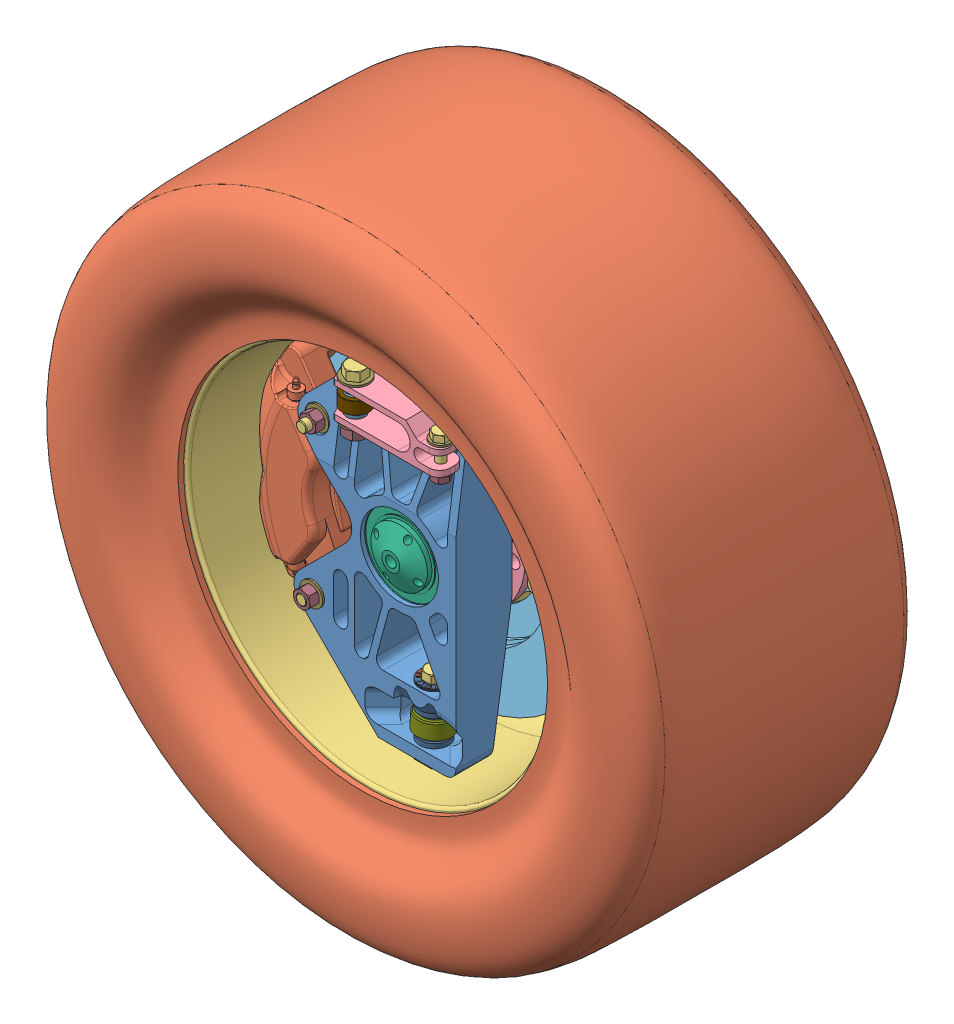
SolidWorks assembly CornerLF_Complete, configuration Default. Lengths in mm.
Overall size (777.29 777.29 255.79).
80 component instances, 30 part files, 180 mates.
Components (placement in the parent):
- UprighntLFLugBillet-4: UprighntLFLugBillet [Final Part] at origin size (558 599.44 88.5)
- TireFront-2: TireFront [Default] at (0 0 -3.67) x (-0.562655 -0.826691 0) z (0 0 1) size (559.46 559.46 255.79)
- WheelFront7J13-2: WheelFront7J13 [Default] at (0 0 -6.73) x (-0.953763 -0.30056 0) z (0 0 -1) size (363 363 191.1)
- SteeringArm-2: SteeringArm [Finished Part Left] at (-42.5 126.5 57.625) size (110 32.34 39)
- BrakeDiscWilwood160-3450-1: BrakeDiscWilwood160-3450 [Default] at (0 0 -3.38) x (-0.953763 -0.30056 0) z (0 0 1) size (266.7 266.7 20)
- BearingWheelCivicFront-1: BearingWheelCivicFront [Default] at (0 0 21.82) x (-0.973136 -0.230231 0) z (0 0 1) size (73.1 73.1 55.34)
- WheelNut-1: WheelNut [Default] at (-0.0272 -0.0421 -52.1943) x (0 0 -1) z (0.976774 0.21427 0) size (26.97 65 74.13)
- WheelDrivePin-1: WheelDrivePin [Default] at (45.3991 14.3067 -6.38) x (-0.73494 0.678133 0) z (0.678133 0.73494 0) size (19.05 44.86 17)
- WheelDrivePin-2: WheelDrivePin [Default] at (-45.3991 -14.3067 -6.38) x (0.925266 0.379318 0) z (0.379318 -0.925266 0) size (19.05 44.86 17)
- WheelDrivePin-3: WheelDrivePin [Default] at (-14.3067 45.3991 -6.38) x (0.256263 -0.966607 0) z (-0.966607 -0.256263 0) size (19.05 44.86 17)
- WheelDrivePin-4: WheelDrivePin [Default] at (14.3067 -45.3991 -6.38) x (0.572125 0.820166 0) z (0.820166 -0.572125 0) size (19.05 44.86 17)
- Pin625-1: Pin625 [Default] at (15.843 -96.8918 50.4139) size (25.4 58 20)
- Washer9x25x4-1: Washer9x25x4 [Default] at (15.843 -92.8918 50.4139) x (-0.99915 0 -0.041233) z (-0.041233 0 0.99915) size (25.4 4 25.4)
- Basic Internal Retaining Ring_am-1: Basic Internal Retaining Ring_am [B27.7M - 3BM1-72] at (0 0 21.667) x (0.998259 0.058987 0) z (0 0 1) size (76.5 74.92 2.4)
- Flat Washer Type A Narrow_AI-5: Flat Washer Type A Narrow_AI [Preferred Narrow FW 0.3125] at (-29.5 126.5 68.625) x (0 0 -1) z (-0.926229 0.376962 0) size (1.65 17.48 17.48)
- Flat Washer Type A Narrow_AI-6: Flat Washer Type A Narrow_AI [Preferred Narrow FW 0.3125] at (32.5 126.5 68.625) x (0 0 -1) z (-0.352455 -0.935829 0) size (1.65 17.48 17.48)
- Flat Washer Type A Narrow_AI-7: Flat Washer Type A Narrow_AI [Preferred Narrow FW 0.3125] at (32.5 126.5 40.625) x (0 0 1) z (1 0 0) size (1.65 17.48 17.48)
- Flat Washer Type A Narrow_AI-8: Flat Washer Type A Narrow_AI [Preferred Narrow FW 0.3125] at (-29.5 126.5 40.625) x (0 0 1) z (-1 -0.000001 0) size (1.65 17.48 17.48)
- Hex Nut_AI-7: Hex Nut_AI [HNUT 0.3125-24-D-N] at (32.5 126.5 32.0398) x (0.923728 0.383049 0) z (0 0 -1) size (12.7 14.66 6.93)
- Hex Nut_AI-8: Hex Nut_AI [HNUT 0.3125-24-D-N] at (-29.5 126.5 32.0398) x (0.923728 0.383049 0) z (0 0 -1) size (12.7 14.66 6.93)
- bush437x500x345-1: bush437x500x345 [Default] at (-16.1 133.7499 88.525) x (-0.828182 0 0.56046) z (-0.56046 0 -0.828182) size (16 8.75 16)
- bush437x500x345-2: bush437x500x345 [Default] at (-16.1 119.2501 88.525) x (0.498132 0 0.867101) z (0.867101 0 -0.498132) size (16 8.75 16)
- BearingSpherical625-1: BearingSpherical625 [Default] at (15.843 -125.485 50.4139) x (0.935451 0 -0.353457) z (0.353457 0 0.935451) size (34.77 22.58 34.87) (flexible)
  - SphericalBearingBall625-1: SphericalBearingBall625 [Default] x (1 0 0) z (0 -1 0) size (26.97 32.6 22.58)
  - SphericalBeaingRace625-1: SphericalBeaingRace625 [Default] x (0.988426 -0.029089 0.148889) z (-0.035405 -0.998574 0.039949) size (30.16 30.16 14.4)
- SpacerSteeringArm3mm-1: SpacerSteeringArm3mm [Default] at (-29.5 126.5 48.625) size (26 32 3)
- SpacerSteeringArm3mm-2: SpacerSteeringArm3mm [Default] at (-29.5 126.5 51.625) x (1 0 0) z (0 0 -1) size (26 32 3)
- SpacerSteeringArm3mm-3: SpacerSteeringArm3mm [Default] at (32.5 126.5 48.625) x (-1 0 0) z (0 0 1) size (26 32 3)
- SpacerSteeringArm3mm-4: SpacerSteeringArm3mm [Default] at (32.5 126.5 51.625) x (-1 0 0) z (0 0 1) size (26 32 3)
- SphericalBearing437in-1: SphericalBearing437in [Default] at (-16.1 126.5 88.525) x (0.999488 0 -0.032002) z (0 -1 0) size (23.81 23.81 14.27) (flexible)
  - SphericalBearing437Race-1: SphericalBearing437Race [Default] at origin size (23.81 23.81 11.23)
  - SphericalBearing437Ball-1: SphericalBearing437Ball [Default] at origin size (19.84 19.84 14.27)
- CaliperWilwood120-6816-1: CaliperWilwood120-6816 [Default] at (-77.1694 0 31.975) x (0 1 0) z (0 0 1) size (178.34 86.45 111.92)
- Flat Washer Type A Narrow_AI-1: Flat Washer Type A Narrow_AI [Preferred Narrow FW 0.375] at (-77.1694 66.7 27.025) x (0 0 1) z (-0.886278 -0.463153 0) size (1.65 20.62 20.62)
- Flat Washer Type A Narrow_AI-2: Flat Washer Type A Narrow_AI [Preferred Narrow FW 0.375] at (-77.1694 -66.7 27.025) x (0 0 1) z (-0.723569 -0.690252 0) size (1.65 20.62 20.62)
- Flat Washer Type A Narrow_AI-3: Flat Washer Type A Narrow_AI [Preferred Narrow FW 0.375] at (-77.1694 -66.7 65.625) x (0 0 -1) z (1 0 0) size (1.65 20.62 20.62)
- Flat Washer Type A Narrow_AI-4: Flat Washer Type A Narrow_AI [Preferred Narrow FW 0.375] at (-77.1694 66.7 60.225) x (0 0 -1) z (1 0 0) size (1.65 20.62 20.62)
- Hex Bolt_AI-1: Hex Bolt_AI [HBOLT 0.3750-24x2x1-N] at (-77.1694 66.7 18.5668) x (0 0 1) z (-1 0 0) size (57.61 16.48 14.27)
- Hex Bolt_AI-2: Hex Bolt_AI [HBOLT 0.3750-24x2x1-N] at (-77.1694 -66.7 18.5668) x (0 0 1) z (-1 0 0) size (57.61 16.48 14.27)
- Hex Nut_AI-1: Hex Nut_AI [HNUT 0.3750-24-D-N] at (-77.1694 66.7 70.4358) size (14.27 16.48 8.56)
- Hex Nut_AI-2: Hex Nut_AI [HNUT 0.3750-24-D-N] at (-77.1694 -66.7 75.8358) x (-0.310782 -0.950481 0) z (0 0 1) size (14.27 16.48 8.56)
- WheelHubHondaCivic-1: WheelHubHondaCivic [Default] at (0 0 21.82) x (-0.996181 0.087308 0) z (0 0 -1) size (120.8 125.54 59.3)
- AdapterWheelHubToDisc-1: AdapterWheelHubToDisc [Finished Part] at (0 0 5.62) x (-0.953763 -0.30056 0) z (0 0 1) size (138.98 157.7 6)
- CVjointCivicOuterMod-1: CVjointCivicOuterMod [Default] at (0 0 116.42) x (0 0 -1) z (0.454803 0.890592 0) size (91.51 50.5 50.5)
- NutHondaCivWhlBrngRet-1: NutHondaCivWhlBrngRet [Default] at (0 0 -2.08) x (-0.872533 0.488555 0) z (0 0 -1) size (36.6 36.6 19.8)
- AxleStub-1: AxleStub [Default] at (0 0 3.92) x (0.99636 -0.085241 0) z (0 0 1) size (56.9 57.5 80.26)
- Flat Washer Type A Narrow_AI-23: Flat Washer Type A Narrow_AI [Preferred Narrow FW 0.3125] at (20.9941 -66.6203 5.62) x (0 0 -1) z (1 0 0) size (1.65 17.48 17.48)
- Flat Washer Type A Narrow_AI-24: Flat Washer Type A Narrow_AI [Preferred Narrow FW 0.3125] at (-47.1978 -51.4916 5.62) x (0 0 -1) z (1 0 0) size (1.65 17.48 17.48)
- Flat Washer Type A Narrow_AI-25: Flat Washer Type A Narrow_AI [Preferred Narrow FW 0.3125] at (-68.192 15.1287 5.62) x (0 0 -1) z (1 0 0) size (1.65 17.48 17.48)
- Flat Washer Type A Narrow_AI-26: Flat Washer Type A Narrow_AI [Preferred Narrow FW 0.3125] at (-20.9941 66.6203 5.62) x (0 0 -1) z (1 0 0) size (1.65 17.48 17.48)
- Flat Washer Type A Narrow_AI-27: Flat Washer Type A Narrow_AI [Preferred Narrow FW 0.3125] at (47.1978 51.4916 5.62) x (0 0 -1) z (1 0 0) size (1.65 17.48 17.48)
- Flat Washer Type A Narrow_AI-28: Flat Washer Type A Narrow_AI [Preferred Narrow FW 0.3125] at (68.192 -15.1287 5.62) x (0 0 -1) z (1 0 0) size (1.65 17.48 17.48)
- Hex Bolt_AI-3: Hex Bolt_AI [HBOLT 0.3125-24x0.75x0.75-N] at (20.9941 -66.6203 13.24) x (0 0 -1) z (1 0 0) size (25.02 14.66 12.7)
- Hex Bolt_AI-4: Hex Bolt_AI [HBOLT 0.3125-24x0.75x0.75-N] at (-47.1978 -51.4916 13.24) x (0 0 -1) z (1 0 0) size (25.02 14.66 12.7)
- Hex Bolt_AI-5: Hex Bolt_AI [HBOLT 0.3125-24x0.75x0.75-N] at (-68.192 15.1287 13.24) x (0 0 -1) z (1 0 0) size (25.02 14.66 12.7)
- Hex Bolt_AI-6: Hex Bolt_AI [HBOLT 0.3125-24x0.75x0.75-N] at (-20.9941 66.6203 13.24) x (0 0 -1) z (1 0 0) size (25.02 14.66 12.7)
- Hex Bolt_AI-7: Hex Bolt_AI [HBOLT 0.3125-24x0.75x0.75-N] at (47.1978 51.4916 13.24) x (0 0 -1) z (1 0 0) size (25.02 14.66 12.7)
- Hex Bolt_AI-8: Hex Bolt_AI [HBOLT 0.3125-24x0.75x0.75-N] at (68.192 -15.1287 13.24) x (0 0 -1) z (1 0 0) size (25.02 14.66 12.7)
- Hex Nut_AI-16: Hex Nut_AI [HNUT 0.3125-24-D-N] at (20.9941 -66.6203 -10.3142) x (0.923728 0.383049 0) z (0 0 -1) size (12.7 14.66 6.93)
- Hex Nut_AI-17: Hex Nut_AI [HNUT 0.3125-24-D-N] at (68.192 -15.1287 -3.38) x (0.080122 0.996785 0) z (0 0 1) size (12.7 14.66 6.93)
- Hex Nut_AI-18: Hex Nut_AI [HNUT 0.3125-24-D-N] at (47.1978 51.4916 -10.3142) x (0.923728 0.383049 0) z (0 0 -1) size (12.7 14.66 6.93)
- Hex Nut_AI-19: Hex Nut_AI [HNUT 0.3125-24-D-N] at (-20.9941 66.6203 -10.3142) x (0.923728 0.383049 0) z (0 0 -1) size (12.7 14.66 6.93)
- Hex Nut_AI-20: Hex Nut_AI [HNUT 0.3125-24-D-N] at (-68.192 15.1287 -10.3142) x (0.923728 0.383049 0) z (0 0 -1) size (12.7 14.66 6.93)
- Hex Nut_AI-21: Hex Nut_AI [HNUT 0.3125-24-D-N] at (-47.1978 -51.4916 -10.3142) x (0.923728 0.383049 0) z (0 0 -1) size (12.7 14.66 6.93)
- SpacerWheelHubToWheel-1: SpacerWheelHubToWheel [Default] at (0 0 -6.73) x (-0.953763 -0.30056 0) z (0 0 1) size (117.5 117.5 6.35)
- Bush16x19x4-1: Bush16x19x4 [Lower Bushing] at (15.843 -139.2 50.4139) x (-0.837169 0 -0.546944) z (0.546944 0 -0.837169) size (25.4 13.9 25.4)
- Bush16x19x4-2: Bush16x19x4 [Upper Bushing] at (15.843 -111.86 50.4139) x (0.401704 0 0.915769) z (0.915769 0 -0.401704) size (25.4 20.96 25.4)
- Flat Washer Type A Narrow_AI-29: Flat Washer Type A Narrow_AI [Preferred Narrow FW 0.4375] at (-16.1 142.5 88.525) x (0 -1 0) z (-0.546944 0 -0.837169) size (1.65 23.42 23.42)
- Flat Washer Type A Narrow_AI-30: Flat Washer Type A Narrow_AI [Preferred Narrow FW 0.4375] at (-16.1 110.5 88.525) x (0 1 0) z (0.546944 0 0.837169) size (1.65 23.42 23.42)
- Hex Nut_AI-22: Hex Nut_AI [HNUT 0.4375-20-D-N] at (-16.1 99.07 88.525) x (-0.837169 0 0.546944) z (0 -1 0) size (17.48 20.18 9.78)
- Flat Washer Type A Narrow_AI-31: Flat Washer Type A Narrow_AI [Preferred Narrow FW 0.3125] at (59.9 110.5 88.525) x (0 1 0) z (0.546944 0 0.837169) size (1.65 17.48 17.48)
- Flat Washer Type A Narrow_AI-32: Flat Washer Type A Narrow_AI [Preferred Narrow FW 0.3125] at (59.9 132.0562 88.525) x (0 -1 0) z (-0.546944 0 -0.837169) size (1.65 17.48 17.48)
- Hex Nut_AI-23: Hex Nut_AI [HNUT 0.3125-24-D-N] at (59.9 101.9148 88.525) x (-0.837169 0 0.546944) z (0 -1 0) size (12.7 14.66 6.93)
- Hex Bolt_AI-9: Hex Bolt_AI [HBOLT 0.4375-20x1.75x1.75-N] at (-16.1 152.1774 88.525) x (0 -1 0) z (-0.546944 0 -0.837169) size (52.48 18.33 15.88)
- Hex Bolt_AI-10: Hex Bolt_AI [HBOLT 0.3125-24x1.25x1.25-N] at (59.9 139.6763 88.525) x (0 -1 0) z (-0.546944 0 -0.837169) size (37.72 14.66 12.7)
- Hex Bolt_AI-11: Hex Bolt_AI [HBOLT 0.375-24x1x1-N] at (15.843 -86.0846 50.4139) x (0 -1 0) z (0 0 1) size (32.21 16.48 14.27)
- Hex Bolt_AI-12: Hex Bolt_AI [HBOLT 0.3125-24x1.375x0.875-N] at (-29.5 126.5 76.245) x (0 0 -1) z (1 0 0) size (40.89 14.66 12.7)
- Hex Bolt_AI-13: Hex Bolt_AI [HBOLT 0.3125-24x1.375x0.875-N] at (32.5 126.5 76.245) x (0 0 -1) z (1 0 0) size (40.89 14.66 12.7)
- Flat Washer Type A Wide_AI-1: Flat Washer Type A Wide_AI [Preferred Wide FW 0.375] at (15.843 -92.8918 50.4139) x (0 1 0) z (1 0 0) size (2.11 25.4 25.4)
- AxleStubPin-1: AxleStubPin [Default] at (1.3162 15.0174 3.17) size (6.35 6.35 9.5)
Mates (geometry in assembly coordinates):
- Concentric1: concentric: cylinder of assembly; cone of assembly; cylinder of TireFront-2 through (0 0 142.5814) axis (0 0 1) radius 165; cone of WheelFront7J13-2 through (0 0 83.0288) axis (0 0 -1)
- Concentric241: concentric: cylinder of assembly; cylinder of assembly; cylinder of Pin625-1 through (15.843 -150.8918 50.4139) axis (0 1 0) radius 7.9375; cylinder of UprighntLFLugBillet-4 through (15.843 -149 50.4139) axis (0 1 0) radius 9.525
- Concentric251: concentric: cylinder of assembly; cylinder of assembly; cylinder of Washer9x25x4-1 through (15.843 -96.8918 50.4139) axis (0 1 0) radius 4.7625; cylinder of Pin625-1 through (15.843 -150.8918 50.4139) axis (0 1 0) radius 7.9375
- Coincident221: coincident: plane of assembly; plane of assembly; plane of Pin625-1 through (15.843 -96.8918 50.4139) normal (0 1 0); plane of Washer9x25x4-1 through (15.843 -96.8918 50.4139) normal (0 -1 0)
- Concentric2621: concentric: cylinder of assembly; cylinder of assembly; cylinder of Basic Internal Retaining Ring_am-1 through (0 0 19.267) axis (0 0 1) radius 38.25; cylinder of UprighntLFLugBillet-4 through (0 0 61.82) axis (0 0 -1) radius 36.5
- Concentric26221: concentric: cylinder of assembly; cylinder of assembly; cylinder of SteeringArm-2 through (-29.5 126.5 99.625) axis (0 0 -1) radius 4.1021; cylinder of Flat Washer Type A Narrow_AI-5 through (-29.5 126.5 103.55) axis (0 0 1) radius 4.3688
- Coincident2321: coincident: plane of assembly; plane of SteeringArm-2 through (12.8365 126.7309 68.625) normal (0 0 1); plane of Flat Washer Type A Narrow_AI-5 through (-31.1469 122.4535 68.625) normal (0 0 -1)
- Concentric26231: concentric: cylinder of assembly; cylinder of assembly; cylinder of SteeringArm-2 through (32.5 126.5 99.625) axis (0 0 -1) radius 4.1021; cylinder of Flat Washer Type A Narrow_AI-6 through (32.5 126.5 103.55) axis (0 0 1) radius 4.3688
- Coincident2331: coincident: plane of assembly; plane of assembly; plane of SteeringArm-2 through (12.8365 126.7309 68.625) normal (0 0 1); plane of Flat Washer Type A Narrow_AI-6 through (36.5884 124.9602 68.625) normal (0 0 -1)
- Coincident2341: coincident: plane of assembly; plane of assembly; plane of UprighntLFLugBillet-4 through (38.5625 118.4375 40.625) normal (0 0 -1); plane of Flat Washer Type A Narrow_AI-7 through (32.5 122.1312 40.625) normal (0 0 1)
- Coincident2351: coincident: plane of assembly; plane of assembly; plane of UprighntLFLugBillet-4 through (38.5625 118.4375 40.625) normal (0 0 -1); plane of Flat Washer Type A Narrow_AI-8 through (-29.5 130.8688 40.625) normal (0 0 1)
- Concentric26291: concentric: cylinder of assembly; cylinder of assembly; cylinder of Flat Washer Type A Narrow_AI-7 through (32.5 126.5 5.7) axis (0 0 -1) radius 4.3688; cylinder of Hex Nut_AI-7 through (32.5 126.5 57.0773) axis (0 0 -1) radius 3.9688
- Coincident2391: coincident: plane of assembly; plane of assembly; plane of Flat Washer Type A Narrow_AI-7 through (32.5 117.7624 38.974) normal (0 0 -1); plane of Hex Nut_AI-7 through (35.3086 119.7269 38.974) normal (0 0 1)
- Concentric26301: concentric: cylinder of assembly; cylinder of assembly; cylinder of Flat Washer Type A Narrow_AI-8 through (-29.5 126.5 5.7) axis (0 0 -1) radius 4.3688; cylinder of Hex Nut_AI-8 through (-29.5 126.5 57.0773) axis (0 0 -1) radius 3.9688
- Coincident2401: coincident: plane of assembly; plane of assembly; plane of Flat Washer Type A Narrow_AI-8 through (-29.5 135.2376 38.974) normal (0 0 -1); plane of Hex Nut_AI-8 through (-26.6914 119.7269 38.974) normal (0 0 1)
- Concentric2636: concentric: cylinder of assembly; cylinder of assembly; cylinder of SteeringArm-2 through (-16.1 110.5 88.525) axis (0 1 0) radius 6.35; cylinder of bush437x500x345-1 through (-16.1 137.6125 88.525) axis (0 -1 0) radius 5.5563
- Concentric2637: concentric: cylinder of assembly; cylinder of assembly; cylinder of SteeringArm-2 through (-16.1 110.5 88.525) axis (0 1 0) radius 6.35; cylinder of bush437x500x345-2 through (-16.1 115.3875 88.525) axis (0 1 0) radius 5.5563
- Coincident245: coincident: plane of assembly; plane of assembly; plane of SteeringArm-2 through (-42.5 137.6125 135.625) normal (0 -1 0); plane of bush437x500x345-1 through (-16.1 137.6125 88.525) normal (0 1 0)
- Coincident246: coincident: plane of assembly; plane of assembly; plane of SteeringArm-2 through (-42.5 115.3875 135.625) normal (0 1 0); plane of bush437x500x345-2 through (-16.1 115.3875 88.525) normal (0 -1 0)
- Distance1: distance = 12 mm: plane of assembly; plane of assembly; plane of UprighntLFLugBillet-4 through (38.5625 118.4375 48.625) normal (0 0 1); plane of SteeringArm-2 through (-42.5 142.5 60.625) normal (0 0 -1)
- Concentric26303: concentric: cylinder of assembly; cylinder of assembly; cylinder of Pin625-1 through (15.843 -150.8918 50.4139) axis (0 1 0) radius 7.9375; cylinder of BearingSpherical625-1/SphericalBearingBall625-1 through (15.843 -115.5936 50.4139) axis (0 1 0) radius 7.94
- Coincident2402: coincident: point of UprighntLFLugBillet-4; point of BearingSpherical625-1/SphericalBearingBall625-1
- Coincident2406: coincident: plane of assembly; plane of assembly; plane of SpacerSteeringArm3mm-1 through (-14.5 110.5 48.625) normal (0 0 -1); plane of UprighntLFLugBillet-4 through (38.5625 118.4375 48.625) normal (0 0 1)
- Concentric26308: concentric: cylinder of assembly; cylinder of assembly; cylinder of SpacerSteeringArm3mm-3 through (32.5 126.5 51.625) axis (0 0 -1) radius 4.1021; cylinder of SpacerSteeringArm3mm-4 through (32.5 126.5 54.625) axis (0 0 -1) radius 4.1021
- Coincident2407: coincident: plane of assembly; plane of assembly; plane of SpacerSteeringArm3mm-3 through (17.5 142.5 51.625) normal (0 0 1); plane of SpacerSteeringArm3mm-4 through (17.5 142.5 51.625) normal (0 0 -1)
- Coincident2408: coincident: plane of assembly; plane of assembly; plane of SpacerSteeringArm3mm-1 through (-14.5 110.5 51.625) normal (0 0 1); plane of SpacerSteeringArm3mm-2 through (-14.5 142.5 51.625) normal (0 0 1)
- Coincident2409: coincident: plane of assembly; plane of assembly; plane of SpacerSteeringArm3mm-3 through (17.5 142.5 48.625) normal (0 0 -1); plane of UprighntLFLugBillet-4 through (38.5625 118.4375 48.625) normal (0 0 1)
- Concentric26310: concentric: cylinder of SteeringArm-2 through (-16.1 110.5 88.525) axis (0 1 0) radius 6.35; cylinder of ? through (-16.1 132.1134 88.525) axis (0 -1 0) radius 11.9062
- Concentric26311: concentric: sphere of SteeringArm-2; unknown of ?
- Distance4: distance = 102 mm: line of CaliperWilwood120-6816-1 through (-77.1694 66.7 31.975) axis (0 0 1); line of BearingWheelCivicFront-1 through (0 0 13.2488) axis (0 0 1)
- Distance5: distance = 102 mm: line of CaliperWilwood120-6816-1 through (-77.1694 -66.7 49.225) axis (0 0 -1); line of BearingWheelCivicFront-1 through (0 0 13.2488) axis (0 0 1)
- Parallel1: parallel: plane of assembly through (0 0 0) normal (0 0 1); plane of CaliperWilwood120-6816-1 through (-77.1694 0 31.975) normal (0 0 1); plane of assembly
- Distance6: distance = 10.287 mm: plane of assembly; plane of assembly; plane of BrakeDiscWilwood160-3450-1 through (0 0 -3.38) normal (0 0 1); plane of CaliperWilwood120-6816-1 through (-77.1694 0 7.075) normal (0 0 1)
- Parallel2: parallel: plane of assembly through (0 0 0) normal (1 0 0); plane of CaliperWilwood120-6816-1 through (-77.1694 0 31.975) normal (-1 0 0); plane of assembly
- Concentric263402: concentric: cylinder of Flat Washer Type A Narrow_AI-1 through (-77.1694 66.7 -7.9) axis (0 0 -1) radius 5.1562; cylinder of Hex Bolt_AI-1 through (-77.1694 66.7 18.5668) axis (0 0 -1) radius 4.7625
- Coincident24383: coincident: plane of UprighntLFLugBillet-4 through (-77.191 66.675 27.025) normal (0 0 -1); plane of Flat Washer Type A Narrow_AI-1 through (-79.5575 71.2698 27.025) normal (0 0 1)
- Concentric263403: concentric: cylinder of Flat Washer Type A Narrow_AI-2 through (-77.1694 -66.7 -7.9) axis (0 0 -1) radius 5.1562; cylinder of Hex Bolt_AI-2 through (-77.1694 -66.7 18.5668) axis (0 0 -1) radius 4.7625
- Coincident24384: coincident: plane of UprighntLFLugBillet-4 through (-77.191 -66.675 27.025) normal (0 0 -1); plane of Flat Washer Type A Narrow_AI-2 through (-80.7284 -62.9691 27.025) normal (0 0 1)
- Coincident24385: coincident: plane of UprighntLFLugBillet-4 through (0 0 65.625) normal (0 0 1); plane of Flat Washer Type A Narrow_AI-3 through (-77.1694 -61.5438 65.625) normal (0 0 -1)
- Concentric263405: concentric: cylinder of Flat Washer Type A Narrow_AI-4 through (-77.1694 66.7 95.15) axis (0 0 1) radius 5.1562; cylinder of Hex Bolt_AI-1 through (-77.1694 66.7 18.5668) axis (0 0 -1) radius 4.7625
- Coincident24386: coincident: plane of UprighntLFLugBillet-4 through (-77.191 66.675 60.225) normal (0 0 1); plane of Flat Washer Type A Narrow_AI-4 through (-77.1694 71.8562 60.225) normal (0 0 -1)
- Coincident24387: coincident: plane of Flat Washer Type A Narrow_AI-1 through (-81.9456 75.8397 25.374) normal (0 0 -1); plane of Hex Bolt_AI-1 through (-77.1694 74.9416 25.374) normal (0 0 1)
- Coincident24388: coincident: plane of Flat Washer Type A Narrow_AI-2 through (-84.2875 -59.2383 25.374) normal (0 0 -1); plane of Hex Bolt_AI-2 through (-77.1694 -58.4584 25.374) normal (0 0 1)
- Concentric263408: concentric: cylinder of Hex Bolt_AI-1 through (-77.1694 66.7 18.5668) axis (0 0 -1) radius 4.7625; cylinder of Hex Nut_AI-1 through (-77.1694 66.7 45.3983) axis (0 0 1) radius 4.7625
- Coincident24389: coincident: plane of Flat Washer Type A Narrow_AI-4 through (-77.1694 77.0124 61.876) normal (0 0 1); plane of Hex Nut_AI-1 through (-91.4442 66.7 61.876) normal (0 0 -1)
- Concentric263409: concentric: cylinder of Hex Bolt_AI-2 through (-77.1694 -66.7 18.5668) axis (0 0 -1) radius 4.7625; cylinder of Hex Nut_AI-2 through (-77.1694 -66.7 50.7983) axis (0 0 1) radius 4.7625
- Coincident24390: coincident: plane of Flat Washer Type A Narrow_AI-3 through (-77.1694 -56.3876 67.276) normal (0 0 1); plane of Hex Nut_AI-2 through (-72.733 -53.1321 67.276) normal (0 0 -1)
- Coincident24406: coincident: plane of UprighntLFLugBillet-4 through (38.5 -147.031 -21.5) normal (0 -1 0); plane of ? through (15.843 -149 50.4139) normal (0 1 0)
- Concentric263421: concentric: cylinder of ? through (15.843 -109.031 -50.4139) axis (0 1 0) radius 3.4544; cylinder of ? through (15.843 -95 50.4139) axis (0 1 0) radius 4.7625
- Coincident24407: coincident: plane of ? through (15.843 -95 50.4139) normal (0 1 0); plane of ? through (20.6055 -99.031 -50.4139) normal (0 -1 0)
- Concentric263423: concentric: cylinder of assembly; cylinder of assembly; cylinder of SteeringArm-2 through (-29.5 126.5 99.625) axis (0 0 1) radius 4.1021; cylinder of Flat Washer Type A Narrow_AI-5 through (-29.5 126.5 103.55) axis (0 0 1) radius 4.3688
- Coincident24409: coincident: plane of ? through (12.8365 126.7309 -60.2175) normal (0 0 -1); plane of Flat Washer Type A Narrow_AI-5 through (-31.1469 122.4535 68.625) normal (0 0 -1)
- Concentric263424: concentric: cylinder of assembly; cylinder of assembly; cylinder of SteeringArm-2 through (32.5 126.5 99.625) axis (0 0 -1) radius 4.1021; cylinder of Flat Washer Type A Narrow_AI-6 through (32.5 126.5 103.55) axis (0 0 1) radius 4.3688
- Coincident24410: coincident: plane of ? through (12.8365 126.7309 -60.2175) normal (0 0 -1); plane of Flat Washer Type A Narrow_AI-6 through (36.5884 124.9602 68.625) normal (0 0 -1)
- Concentric263425: concentric: cylinder of assembly; cylinder of UprighntLFLugBillet-4 through (29.5 126.5 -40.2175) axis (0 0 -1) radius 3.9688; cylinder of Flat Washer Type A Narrow_AI-7 through (32.5 126.5 5.7) axis (0 0 -1) radius 4.3688
- Coincident24411: coincident: plane of assembly; plane of assembly; plane of UprighntLFLugBillet-4 through (38.5625 118.4375 48.625) normal (0 0 1); plane of Flat Washer Type A Narrow_AI-7 through (32.5 122.1312 40.625) normal (0 0 1)
- Coincident24415: coincident: plane of assembly; plane of assembly; plane of Flat Washer Type A Narrow_AI-7 through (32.5 117.7624 38.974) normal (0 0 -1); plane of Hex Nut_AI-7 through (35.3086 119.7269 32.0398) normal (0 0 -1)
- Coincident24417: coincident: plane of assembly; plane of assembly; plane of UprighntLFLugBillet-4 through (34.0068 0 19.267) normal (0 0 1); plane of Basic Internal Retaining Ring_am-1 through (0 0 19.267) normal (0 0 -1)
- Concentric263429: concentric: cylinder of assembly; cylinder of UprighntLFLugBillet-4 through (-29.5 126.5 -40.2175) axis (0 0 -1) radius 3.9688; cylinder of SteeringArm-2 through (-29.5 126.5 99.625) axis (0 0 1) radius 4.1021
- Concentric263430: concentric: cylinder of assembly; cylinder of UprighntLFLugBillet-4 through (29.5 126.5 -40.2175) axis (0 0 -1) radius 3.9688; cylinder of SteeringArm-2 through (32.5 126.5 99.625) axis (0 0 -1) radius 4.1021
- Concentric263431: concentric: cylinder of assembly; cylinder of assembly; cylinder of SteeringArm-2 through (-16.1 110.5 88.525) axis (0 1 0) radius 6.35; cylinder of bush437x500x345-1 through (-16.1 137.6125 88.525) axis (0 -1 0) radius 5.5563
- Concentric263432: concentric: cylinder of assembly; cylinder of assembly; cylinder of SteeringArm-2 through (-16.1 110.5 88.525) axis (0 1 0) radius 6.35; cylinder of bush437x500x345-2 through (-16.1 115.3875 88.525) axis (0 1 0) radius 5.5563
- Coincident24418: coincident: plane of assembly; plane of assembly; plane of SteeringArm-2 through (-42.5 137.6125 135.625) normal (0 -1 0); plane of bush437x500x345-1 through (-16.1 137.6125 88.525) normal (0 1 0)
- Coincident24419: coincident: plane of ? through (-42.5 115.5 -129.2175) normal (0 1 0); plane of bush437x500x345-2 through (-16.1 119.2501 88.525) normal (0 1 0)
- Distance7: distance = 6 mm: plane of assembly; plane of UprighntLFLugBillet-4; plane of SteeringArm-2 through (-42.5 142.5 60.625) normal (0 0 -1)
- Coincident24421: coincident: plane of assembly; plane of UprighntLFLugBillet-4; plane of SpacerSteeringArm3mm-1 through (-14.5 110.5 48.625) normal (0 0 -1)
- Concentric263438: concentric: cylinder of assembly; cylinder of assembly; cylinder of SpacerSteeringArm3mm-3 through (32.5 126.5 51.625) axis (0 0 1) radius 4.1021; cylinder of SpacerSteeringArm3mm-4 through (32.5 126.5 54.625) axis (0 0 1) radius 4.1021
- Coincident24422: coincident: plane of assembly; plane of assembly; plane of SpacerSteeringArm3mm-3 through (17.5 142.5 51.625) normal (0 0 1); plane of SpacerSteeringArm3mm-4 through (17.5 142.5 51.625) normal (0 0 -1)
- Coincident24423: coincident: plane of assembly; plane of assembly; plane of SpacerSteeringArm3mm-1 through (-14.5 110.5 51.625) normal (0 0 1); plane of SpacerSteeringArm3mm-2 through (-14.5 142.5 51.625) normal (0 0 1)
- Coincident24424: coincident: plane of assembly; plane of UprighntLFLugBillet-4; plane of SpacerSteeringArm3mm-3 through (17.5 142.5 48.625) normal (0 0 -1)
- Concentric263470: concentric: cylinder of assembly; cylinder of assembly; cylinder of BearingWheelCivicFront-1 through (0 0 61.82) axis (0 0 -1) radius 19; cylinder of WheelHubHondaCivic-1 through (0 0 21.82) axis (0 0 1) radius 19
- Concentric263471: concentric: cylinder of assembly; cylinder of assembly; cylinder of UprighntLFLugBillet-4 through (0 0 61.82) axis (0 0 -1) radius 36.5; cylinder of BearingWheelCivicFront-1 through (0 0 61.82) axis (0 0 -1) radius 36.55
- Coincident24471: coincident: plane of assembly; plane of assembly; plane of UprighntLFLugBillet-4 through (0 0 61.82) normal (0 0 -1); plane of BearingWheelCivicFront-1 through (0 0 61.82) normal (0 0 1)
- Coincident24472: coincident: plane of assembly; plane of assembly; plane of UprighntLFLugBillet-4 through (-94.191 13.875 49.225) normal (0 0 -1); plane of CaliperWilwood120-6816-1 through (-77.1694 -66.7 49.225) normal (0 0 1)
- Coincident24473: coincident: plane of assembly; plane of assembly; plane of BearingWheelCivicFront-1 through (0 0 21.82) normal (0 0 -1); plane of WheelHubHondaCivic-1 through (1.7025 19.4255 21.82) normal (0 0 1)
- Coincident24474: coincident: plane of assembly; plane of assembly; plane of WheelHubHondaCivic-1 through (5.2734 60.1694 5.62) normal (0 0 -1); plane of AdapterWheelHubToDisc-1 through (9.137 -28.9944 5.62) normal (0 0 1)
- Concentric263474: concentric: cylinder of assembly; cylinder of assembly; cylinder of WheelHubHondaCivic-1 through (0 0 21.82) axis (0 0 1) radius 14.1; cylinder of CVjointCivicOuterMod-1 through (0 0 276.1473) axis (0 0 1) radius 13.5
- Coincident24476: coincident: plane of assembly; plane of assembly; plane of BearingWheelCivicFront-1 through (0 0 61.82) normal (0 0 1); plane of CVjointCivicOuterMod-1 through (-12.023 6.1398 61.82) normal (0 0 -1)
- Concentric263475: concentric: cylinder of assembly; cylinder of assembly; cylinder of SpacerWheelHubToWheel-1 through (0 0 -0.38) axis (0 0 -1) radius 58.75; cylinder of WheelHubHondaCivic-1 through (0 0 21.82) axis (0 0 1) radius 60.4
- Concentric263480: concentric: cylinder of assembly; cylinder of assembly; cylinder of CVjointCivicOuterMod-1 through (0 0 276.1473) axis (0 0 1) radius 10.9; cylinder of NutHondaCivWhlBrngRet-1 through (0 0 -29.8385) axis (0 0 -1) radius 10.2
- Concentric263481: concentric: cylinder of assembly; cylinder of assembly; cylinder of CVjointCivicOuterMod-1 through (0 0 276.1473) axis (0 0 1) radius 10.9; cylinder of AxleStub-1 through (0 0 50.1767) axis (0 0 1) radius 10.9
- Coincident24479: coincident: plane of assembly; plane of assembly; plane of NutHondaCivWhlBrngRet-1 through (4.9833 8.8998 -2.08) normal (0 0 1); plane of AxleStub-1 through (1.4619 17.0876 -2.08) normal (0 0 -1)
- Coincident24480: coincident: plane of assembly; plane of assembly; plane of WheelHubHondaCivic-1 through (1.2223 13.9465 3.92) normal (0 0 -1); plane of AxleStub-1 through (1.6452 19.2298 3.92) normal (0 0 1)
- Coincident24481: coincident: plane of assembly; plane of assembly; plane of WheelDrivePin-3 through (-16.7476 54.606 -0.38) normal (0 0 1); plane of AdapterWheelHubToDisc-1 through (17.6579 -56.0336 -0.38) normal (0 0 -1)
- Concentric263483: concentric: cylinder of assembly; cylinder of WheelDrivePin-3 through (-14.3067 45.3991 65.6665) axis (0 0 1) radius 9.525; cylinder of AdapterWheelHubToDisc-1 through (-14.3067 45.3991 -0.38) axis (0 0 1) radius 6.5481
- Concentric263484: concentric: cylinder of assembly; cylinder of assembly; cylinder of WheelDrivePin-2 through (-45.3991 -14.3067 65.6665) axis (0 0 1) radius 6.35; cylinder of WheelHubHondaCivic-1 through (-45.3991 -14.3067 5.62) axis (0 0 -1) radius 5.7544
- Coincident24482: coincident: plane of assembly; plane of assembly; plane of WheelDrivePin-2 through (-54.2123 -17.9197 -0.38) normal (0 0 1); plane of AdapterWheelHubToDisc-1 through (17.6579 -56.0336 -0.38) normal (0 0 -1)
- Concentric263486: concentric: cylinder of assembly; cylinder of assembly; cylinder of WheelDrivePin-4 through (14.3067 -45.3991 65.6665) axis (0 0 1) radius 6.35; cylinder of WheelHubHondaCivic-1 through (14.3067 -45.3991 5.62) axis (0 0 -1) radius 5.7544
- Coincident24483: coincident: plane of assembly; plane of assembly; plane of WheelDrivePin-4 through (8.8572 -53.2112 -0.38) normal (0 0 1); plane of AdapterWheelHubToDisc-1 through (17.6579 -56.0336 -0.38) normal (0 0 -1)
- Coincident24484: coincident: plane of assembly; plane of assembly; plane of WheelDrivePin-1 through (52.3994 7.8475 -0.38) normal (0 0 1); plane of AdapterWheelHubToDisc-1 through (17.6579 -56.0336 -0.38) normal (0 0 -1)
- Concentric263488: concentric: cylinder of assembly; cylinder of assembly; cylinder of BrakeDiscWilwood160-3450-1 through (0 0 -0.38) axis (0 0 -1) radius 62.75; cylinder of SpacerWheelHubToWheel-1 through (0 0 -0.38) axis (0 0 -1) radius 58.75
- Concentric263490: concentric: cylinder of assembly; cylinder of assembly; cylinder of AdapterWheelHubToDisc-1 through (20.9941 -66.6203 -0.38) axis (0 0 1) radius 4.1021; cylinder of Flat Washer Type A Narrow_AI-23 through (20.9941 -66.6203 40.545) axis (0 0 1) radius 4.3688
- Coincident24486: coincident: plane of assembly; plane of assembly; plane of AdapterWheelHubToDisc-1 through (9.137 -28.9944 5.62) normal (0 0 1); plane of Flat Washer Type A Narrow_AI-23 through (20.9941 -62.2515 5.62) normal (0 0 -1)
- Concentric263491: concentric: cylinder of assembly; cylinder of assembly; cylinder of AdapterWheelHubToDisc-1 through (-47.1978 -51.4916 -0.38) axis (0 0 1) radius 4.1021; cylinder of Flat Washer Type A Narrow_AI-24 through (-47.1978 -51.4916 40.545) axis (0 0 1) radius 4.3688
- Coincident24487: coincident: plane of assembly; plane of assembly; plane of AdapterWheelHubToDisc-1 through (9.137 -28.9944 5.62) normal (0 0 1); plane of Flat Washer Type A Narrow_AI-24 through (-47.1978 -47.1228 5.62) normal (0 0 -1)
- Concentric263492: concentric: cylinder of assembly; cylinder of assembly; cylinder of AdapterWheelHubToDisc-1 through (-68.192 15.1287 -0.38) axis (0 0 1) radius 4.1021; cylinder of Flat Washer Type A Narrow_AI-25 through (-68.192 15.1287 40.545) axis (0 0 1) radius 4.3688
- Coincident24488: coincident: plane of assembly; plane of assembly; plane of AdapterWheelHubToDisc-1 through (9.137 -28.9944 5.62) normal (0 0 1); plane of Flat Washer Type A Narrow_AI-25 through (-68.192 19.4975 5.62) normal (0 0 -1)
- Concentric263493: concentric: cylinder of assembly; cylinder of assembly; cylinder of AdapterWheelHubToDisc-1 through (-20.9941 66.6203 -0.38) axis (0 0 1) radius 4.1021; cylinder of Flat Washer Type A Narrow_AI-26 through (-20.9941 66.6203 40.545) axis (0 0 1) radius 4.3688
- Coincident24489: coincident: plane of assembly; plane of assembly; plane of AdapterWheelHubToDisc-1 through (9.137 -28.9944 5.62) normal (0 0 1); plane of Flat Washer Type A Narrow_AI-26 through (-20.9941 70.9891 5.62) normal (0 0 -1)
- Concentric263494: concentric: cylinder of assembly; cylinder of assembly; cylinder of AdapterWheelHubToDisc-1 through (47.1978 51.4916 -0.38) axis (0 0 1) radius 4.1021; cylinder of Flat Washer Type A Narrow_AI-27 through (47.1978 51.4916 40.545) axis (0 0 1) radius 4.3688
- Coincident24490: coincident: plane of assembly; plane of assembly; plane of AdapterWheelHubToDisc-1 through (9.137 -28.9944 5.62) normal (0 0 1); plane of Flat Washer Type A Narrow_AI-27 through (47.1978 55.8604 5.62) normal (0 0 -1)
- Concentric263495: concentric: cylinder of assembly; cylinder of assembly; cylinder of AdapterWheelHubToDisc-1 through (68.192 -15.1287 -0.38) axis (0 0 1) radius 4.1021; cylinder of Flat Washer Type A Narrow_AI-28 through (68.192 -15.1287 40.545) axis (0 0 1) radius 4.3688
- Coincident24491: coincident: plane of assembly; plane of assembly; plane of AdapterWheelHubToDisc-1 through (9.137 -28.9944 5.62) normal (0 0 1); plane of Flat Washer Type A Narrow_AI-28 through (68.192 -10.7599 5.62) normal (0 0 -1)
- Concentric263496: concentric: cylinder of assembly; cylinder of assembly; cylinder of AdapterWheelHubToDisc-1 through (20.9941 -66.6203 -0.38) axis (0 0 1) radius 4.1021; cylinder of Hex Bolt_AI-3 through (20.9941 -66.6203 13.24) axis (0 0 1) radius 3.9688
- Coincident24492: coincident: plane of assembly; plane of assembly; plane of Flat Washer Type A Narrow_AI-23 through (20.9941 -57.8827 7.271) normal (0 0 1); plane of Hex Bolt_AI-3 through (20.9941 -59.288 7.271) normal (0 0 -1)
- Concentric263497: concentric: cylinder of assembly; cylinder of assembly; cylinder of AdapterWheelHubToDisc-1 through (-47.1978 -51.4916 -0.38) axis (0 0 1) radius 4.1021; cylinder of Hex Bolt_AI-4 through (-47.1978 -51.4916 13.24) axis (0 0 1) radius 3.9688
- Coincident24493: coincident: plane of assembly; plane of assembly; plane of Flat Washer Type A Narrow_AI-24 through (-47.1978 -42.754 7.271) normal (0 0 1); plane of Hex Bolt_AI-4 through (-47.1978 -44.1593 7.271) normal (0 0 -1)
- Concentric263498: concentric: cylinder of assembly; cylinder of assembly; cylinder of AdapterWheelHubToDisc-1 through (-68.192 15.1287 -0.38) axis (0 0 1) radius 4.1021; cylinder of Hex Bolt_AI-5 through (-68.192 15.1287 13.24) axis (0 0 1) radius 3.9688
- Coincident24494: coincident: plane of assembly; plane of assembly; plane of Flat Washer Type A Narrow_AI-25 through (-68.192 23.8663 7.271) normal (0 0 1); plane of Hex Bolt_AI-5 through (-68.192 22.461 7.271) normal (0 0 -1)
- Concentric263499: concentric: cylinder of assembly; cylinder of assembly; cylinder of AdapterWheelHubToDisc-1 through (-20.9941 66.6203 -0.38) axis (0 0 1) radius 4.1021; cylinder of Hex Bolt_AI-6 through (-20.9941 66.6203 13.24) axis (0 0 1) radius 3.9688
- Coincident24495: coincident: plane of assembly; plane of assembly; plane of Flat Washer Type A Narrow_AI-26 through (-20.9941 75.3579 7.271) normal (0 0 1); plane of Hex Bolt_AI-6 through (-20.9941 73.9527 7.271) normal (0 0 -1)
- Concentric263500: concentric: cylinder of assembly; cylinder of assembly; cylinder of AdapterWheelHubToDisc-1 through (47.1978 51.4916 -0.38) axis (0 0 1) radius 4.1021; cylinder of Hex Bolt_AI-7 through (47.1978 51.4916 13.24) axis (0 0 1) radius 3.9688
- Coincident24496: coincident: plane of assembly; plane of assembly; plane of Flat Washer Type A Narrow_AI-27 through (47.1978 60.2292 7.271) normal (0 0 1); plane of Hex Bolt_AI-7 through (47.1978 58.824 7.271) normal (0 0 -1)
- Concentric263501: concentric: cylinder of assembly; cylinder of assembly; cylinder of AdapterWheelHubToDisc-1 through (68.192 -15.1287 -0.38) axis (0 0 1) radius 4.1021; cylinder of Hex Bolt_AI-8 through (68.192 -15.1287 13.24) axis (0 0 1) radius 3.9688
- Coincident24497: coincident: plane of assembly; plane of assembly; plane of Flat Washer Type A Narrow_AI-28 through (68.192 -6.3911 7.271) normal (0 0 1); plane of Hex Bolt_AI-8 through (68.192 -7.7964 7.271) normal (0 0 -1)
- Concentric263503: concentric: cylinder of assembly; cylinder of assembly; cylinder of BrakeDiscWilwood160-3450-1 through (20.9941 -66.6203 7.62) axis (0 0 -1) radius 4.15; cylinder of Hex Bolt_AI-3 through (20.9941 -66.6203 13.24) axis (0 0 1) radius 3.9688
- Concentric263504: concentric: cylinder of assembly; cylinder of assembly; cylinder of Hex Bolt_AI-3 through (20.9941 -66.6203 13.24) axis (0 0 1) radius 3.9688; cylinder of Hex Nut_AI-16 through (20.9941 -66.6203 14.7233) axis (0 0 -1) radius 3.9688
- Coincident24498: coincident: plane of assembly; plane of assembly; plane of BrakeDiscWilwood160-3450-1 through (0 0 -3.38) normal (0 0 -1); plane of Hex Nut_AI-16 through (23.8028 -73.3934 -3.38) normal (0 0 1)
- Concentric263505: concentric: cylinder of assembly; cylinder of assembly; cylinder of Hex Bolt_AI-8 through (68.192 -15.1287 13.24) axis (0 0 1) radius 3.9688; cylinder of Hex Nut_AI-17 through (68.192 -15.1287 -28.4175) axis (0 0 1) radius 3.9688
- Concentric263506: concentric: cylinder of assembly; cylinder of assembly; cylinder of Hex Bolt_AI-7 through (47.1978 51.4916 13.24) axis (0 0 1) radius 3.9688; cylinder of Hex Nut_AI-18 through (47.1978 51.4916 14.7233) axis (0 0 -1) radius 3.9688
- Coincident24499: coincident: plane of assembly; plane of assembly; plane of BrakeDiscWilwood160-3450-1 through (0 0 -3.38) normal (0 0 -1); plane of Hex Nut_AI-18 through (50.0065 44.7185 -3.38) normal (0 0 1)
- Concentric263507: concentric: cylinder of assembly; cylinder of assembly; cylinder of Hex Bolt_AI-6 through (-20.9941 66.6203 13.24) axis (0 0 1) radius 3.9688; cylinder of Hex Nut_AI-19 through (-20.9941 66.6203 14.7233) axis (0 0 -1) radius 3.9688
- Coincident24500: coincident: plane of assembly; plane of assembly; plane of BrakeDiscWilwood160-3450-1 through (0 0 -3.38) normal (0 0 -1); plane of Hex Nut_AI-19 through (-18.1855 59.8472 -3.38) normal (0 0 1)
- Concentric263508: concentric: cylinder of assembly; cylinder of assembly; cylinder of Hex Bolt_AI-5 through (-68.192 15.1287 13.24) axis (0 0 1) radius 3.9688; cylinder of Hex Nut_AI-20 through (-68.192 15.1287 14.7233) axis (0 0 -1) radius 3.9688
- Coincident24501: coincident: plane of assembly; plane of assembly; plane of BrakeDiscWilwood160-3450-1 through (0 0 -3.38) normal (0 0 -1); plane of Hex Nut_AI-20 through (-65.3833 8.3556 -3.38) normal (0 0 1)
- Concentric263509: concentric: cylinder of assembly; cylinder of assembly; cylinder of Hex Bolt_AI-4 through (-47.1978 -51.4916 13.24) axis (0 0 1) radius 3.9688; cylinder of Hex Nut_AI-21 through (-47.1978 -51.4916 14.7233) axis (0 0 -1) radius 3.9688
- Coincident24502: coincident: plane of assembly; plane of assembly; plane of BrakeDiscWilwood160-3450-1 through (0 0 -3.38) normal (0 0 -1); plane of Hex Nut_AI-21 through (-44.3892 -58.2647 -3.38) normal (0 0 1)
- Coincident24503: coincident: plane of assembly; plane of assembly; plane of BrakeDiscWilwood160-3450-1 through (0 0 -3.38) normal (0 0 -1); plane of Hex Nut_AI-17 through (60.8832 -14.5412 -3.38) normal (0 0 1)
- Concentric263510: concentric: cylinder of assembly; cylinder of assembly; cylinder of WheelFront7J13-2 through (0 0 -139.9944) axis (0 0 -1) radius 28.5; cylinder of AxleStub-1 through (0 0 50.1767) axis (0 0 1) radius 27.85
- Coincident24504: coincident: plane of assembly; plane of assembly; plane of WheelFront7J13-2 through (-8.566 27.1822 -6.73) normal (0 0 1); plane of SpacerWheelHubToWheel-1 through (0 0 -6.73) normal (0 0 -1)
- Concentric263511: concentric: cylinder of assembly; cylinder of assembly; cylinder of WheelFront7J13-2 through (45.3991 14.3067 -34.73) axis (0 0 1) radius 6.75; cylinder of WheelDrivePin-1 through (45.3991 14.3067 65.6665) axis (0 0 1) radius 6.6675
- Concentric263512: concentric: cylinder of assembly; cylinder of assembly; cylinder of WheelDrivePin-1 through (45.3991 14.3067 65.6665) axis (0 0 1) radius 6.35; cylinder of WheelHubHondaCivic-1 through (45.3991 14.3067 5.62) axis (0 0 -1) radius 5.7544
- Concentric263513: concentric: cylinder of assembly; cylinder of assembly; cylinder of WheelDrivePin-3 through (-14.3067 45.3991 65.6665) axis (0 0 1) radius 6.35; cylinder of WheelHubHondaCivic-1 through (-14.3067 45.3991 5.62) axis (0 0 -1) radius 5.7544
- Concentric263514: concentric: cylinder of assembly; cylinder of assembly; cylinder of AxleStub-1 through (0 0 50.1767) axis (0 0 1) radius 27.85; cylinder of SpacerWheelHubToWheel-1 through (0 0 -0.38) axis (0 0 -1) radius 34.5
- Coincident24505: coincident: plane of assembly; plane of assembly; plane of AdapterWheelHubToDisc-1 through (17.6579 -56.0336 -0.38) normal (0 0 -1); plane of SpacerWheelHubToWheel-1 through (0 0 -0.38) normal (0 0 1)
- Concentric263515: concentric: cylinder of assembly; cylinder of assembly; cylinder of AdapterWheelHubToDisc-1 through (-14.3067 45.3991 -0.38) axis (0 0 1) radius 6.5481; cylinder of SpacerWheelHubToWheel-1 through (-14.3067 45.3991 -0.38) axis (0 0 -1) radius 9.55
- Concentric263516: concentric: cylinder of assembly; cylinder of assembly; cylinder of Pin625-1 through (15.843 -150.8918 50.4139) axis (0 1 0) radius 7.9375; cylinder of Bush16x19x4-1 through (15.843 -103.4342 50.4139) axis (0 1 0) radius 7.9375
- Coincident24506: coincident: plane of assembly; plane of assembly; plane of UprighntLFLugBillet-4 through (-8.5 -139.2 15.625) normal (0 1 0); plane of Bush16x19x4-1 through (7.869 -139.2 45.2042) normal (0 -1 0)
- Concentric263517: concentric: cylinder of assembly; cylinder of assembly; cylinder of Pin625-1 through (15.843 -150.8918 50.4139) axis (0 1 0) radius 7.9375; cylinder of Bush16x19x4-2 through (15.843 -147.6258 50.4139) axis (0 -1 0) radius 7.9375
- Coincident24507: coincident: plane of assembly; plane of assembly; plane of UprighntLFLugBillet-4 through (-8.5 -111.86 15.625) normal (0 -1 0); plane of Bush16x19x4-2 through (19.6692 -111.86 59.1366) normal (0 1 0)
- Concentric263518: concentric: cylinder of assembly; cylinder of assembly; cylinder of SteeringArm-2 through (-16.1 110.5 88.525) axis (0 1 0) radius 6.35; cylinder of Flat Washer Type A Narrow_AI-29 through (-16.1 177.425 88.525) axis (0 1 0) radius 5.9563
- Coincident24508: coincident: plane of assembly; plane of assembly; plane of SteeringArm-2 through (-42.5 142.5 135.625) normal (0 1 0); plane of Flat Washer Type A Narrow_AI-29 through (-21.0864 142.5 91.7828) normal (0 -1 0)
- Concentric263519: concentric: cylinder of assembly; cylinder of assembly; cylinder of SteeringArm-2 through (-16.1 110.5 88.525) axis (0 1 0) radius 6.35; cylinder of Flat Washer Type A Narrow_AI-30 through (-16.1 75.575 88.525) axis (0 -1 0) radius 5.9563
- Coincident24509: coincident: plane of assembly; plane of assembly; plane of SteeringArm-2 through (-42.5 110.5 135.625) normal (0 -1 0); plane of Flat Washer Type A Narrow_AI-30 through (-21.0864 110.5 91.7828) normal (0 1 0)
- Concentric263520: concentric: cylinder of assembly; cylinder of assembly; cylinder of Flat Washer Type A Narrow_AI-30 through (-16.1 75.575 88.525) axis (0 -1 0) radius 5.9563; cylinder of Hex Nut_AI-22 through (-16.1 124.1075 88.525) axis (0 -1 0) radius 5.5563
- Coincident24510: coincident: plane of assembly; plane of assembly; plane of Flat Washer Type A Narrow_AI-30 through (-25.9027 108.849 94.9294) normal (0 -1 0); plane of Hex Nut_AI-22 through (-21.6183 108.849 80.0785) normal (0 1 0)
- Concentric263521: concentric: cylinder of assembly; cylinder of assembly; cylinder of SteeringArm-2 through (59.9 110.5 88.525) axis (0 1 0) radius 4.1021; cylinder of Flat Washer Type A Narrow_AI-31 through (59.9 75.575 88.525) axis (0 -1 0) radius 4.3688
- Coincident24511: coincident: plane of assembly; plane of assembly; plane of SteeringArm-2 through (-42.5 110.5 135.625) normal (0 -1 0); plane of Flat Washer Type A Narrow_AI-31 through (56.2426 110.5 90.9145) normal (0 1 0)
- Concentric263522: concentric: cylinder of assembly; cylinder of assembly; cylinder of SteeringArm-2 through (59.9 110.5 88.525) axis (0 1 0) radius 4.1021; cylinder of Flat Washer Type A Narrow_AI-32 through (59.9 166.9812 88.525) axis (0 1 0) radius 4.3688
- Coincident24512: coincident: plane of assembly; plane of assembly; plane of SteeringArm-2 through (52.5 132.0562 135.625) normal (0 1 0); plane of Flat Washer Type A Narrow_AI-32 through (56.2426 132.0562 90.9145) normal (0 -1 0)
- Concentric263523: concentric: cylinder of assembly; cylinder of assembly; cylinder of Flat Washer Type A Narrow_AI-31 through (59.9 75.575 88.525) axis (0 -1 0) radius 4.3688; cylinder of Hex Nut_AI-23 through (59.9 126.9523 88.525) axis (0 -1 0) radius 3.9688
- Coincident24513: coincident: plane of assembly; plane of assembly; plane of Flat Washer Type A Narrow_AI-31 through (52.5852 108.849 93.304) normal (0 -1 0); plane of Hex Nut_AI-23 through (55.8896 108.849 82.3866) normal (0 1 0)
- Concentric263524: concentric: cylinder of assembly; cylinder of assembly; cylinder of SteeringArm-2 through (-16.1 110.5 88.525) axis (0 1 0) radius 6.35; cylinder of Hex Bolt_AI-9 through (-16.1 152.1774 88.525) axis (0 1 0) radius 5.5563
- Coincident24514: coincident: plane of assembly; plane of assembly; plane of Flat Washer Type A Narrow_AI-29 through (-25.9027 144.151 94.9294) normal (0 1 0); plane of Hex Bolt_AI-9 through (-23.773 144.151 93.538) normal (0 -1 0)
- Concentric263525: concentric: cylinder of assembly; cylinder of assembly; cylinder of SteeringArm-2 through (59.9 110.5 88.525) axis (0 1 0) radius 4.1021; cylinder of Hex Bolt_AI-10 through (59.9 139.6763 88.525) axis (0 1 0) radius 3.9688
- Coincident24515: coincident: plane of assembly; plane of assembly; plane of Flat Washer Type A Narrow_AI-32 through (52.5852 133.7072 93.304) normal (0 1 0); plane of Hex Bolt_AI-10 through (53.7616 133.7072 92.5354) normal (0 -1 0)
- Coincident24516: coincident: plane of assembly; plane of assembly; plane of SpacerSteeringArm3mm-1 through (-14.5 142.5 51.625) normal (1 0 0); plane of SpacerSteeringArm3mm-2 through (-14.5 110.5 48.625) normal (1 0 0)
- Parallel3: parallel: plane of assembly; plane of assembly; plane of SteeringArm-2 through (19.85 110.5 37.1737) normal (-1 0 0); plane of SpacerSteeringArm3mm-4 through (17.5 110.5 54.625) normal (-1 0 0)
- Parallel4: parallel: plane of assembly; plane of assembly; plane of SteeringArm-2 through (-16.85 110.5 65.625) normal (1 0 0); plane of SpacerSteeringArm3mm-2 through (-14.5 110.5 48.625) normal (1 0 0)
- Coincident24520: coincident: plane of assembly; plane of assembly; plane of SpacerSteeringArm3mm-3 through (17.5 110.5 51.625) normal (-1 0 0); plane of SpacerSteeringArm3mm-4 through (17.5 110.5 54.625) normal (-1 0 0)
- Concentric263526: concentric: cylinder of CaliperWilwood120-6816-1 through (-77.1694 66.7 49.225) axis (0 0 -1) radius 4.95; cylinder of Hex Bolt_AI-1 through (-77.1694 66.7 18.5668) axis (0 0 -1) radius 4.7625
- Concentric263527: concentric: cylinder of Flat Washer Type A Narrow_AI-3 through (-77.1694 -66.7 100.55) axis (0 0 1) radius 5.1562; cylinder of Hex Bolt_AI-2 through (-77.1694 -66.7 18.5668) axis (0 0 -1) radius 4.7625
- Concentric263528: concentric: cylinder of CaliperWilwood120-6816-1 through (-77.1694 -66.7 49.225) axis (0 0 -1) radius 4.95; cylinder of Hex Bolt_AI-2 through (-77.1694 -66.7 18.5668) axis (0 0 -1) radius 4.7625
- Concentric263529: concentric: cylinder of assembly; cylinder of assembly; cylinder of Washer9x25x4-1 through (15.843 -96.8918 50.4139) axis (0 1 0) radius 4.7625; cylinder of Hex Bolt_AI-11 through (15.843 -86.0846 50.4139) axis (0 1 0) radius 4.7625
- Coincident24521: coincident: plane of assembly; plane of assembly; plane of Washer9x25x4-1 through (15.843 -92.8918 50.4139) normal (0 1 0); plane of Hex Bolt_AI-11 through (24.0846 -92.8918 50.4139) normal (0 -1 0)
- Concentric263530: concentric: cylinder of assembly; cylinder of assembly; cylinder of SteeringArm-2 through (-29.5 126.5 99.625) axis (0 0 -1) radius 4.1021; cylinder of Hex Bolt_AI-12 through (-29.5 126.5 76.245) axis (0 0 1) radius 3.9688
- Coincident24522: coincident: plane of assembly; plane of assembly; plane of Flat Washer Type A Narrow_AI-5 through (-32.7937 118.407 70.276) normal (0 0 1); plane of Hex Bolt_AI-12 through (-29.5 133.8323 70.276) normal (0 0 -1)
- Concentric263531: concentric: cylinder of assembly; cylinder of assembly; cylinder of SteeringArm-2 through (32.5 126.5 99.625) axis (0 0 -1) radius 4.1021; cylinder of Hex Bolt_AI-13 through (32.5 126.5 76.245) axis (0 0 1) radius 3.9688
- Coincident24523: coincident: plane of assembly; plane of assembly; plane of Flat Washer Type A Narrow_AI-6 through (40.6769 123.4204 70.276) normal (0 0 1); plane of Hex Bolt_AI-13 through (32.5 133.8323 70.276) normal (0 0 -1)
- Coincident24524: coincident: plane of assembly; plane of assembly; plane of BrakeDiscWilwood160-3450-1 through (0 0 -0.38) normal (0 0 1); plane of AdapterWheelHubToDisc-1 through (17.6579 -56.0336 -0.38) normal (0 0 -1)
- Concentric263533: concentric: cylinder of assembly; cylinder of assembly; cylinder of Pin625-1 through (15.843 -150.8918 50.4139) axis (0 1 0) radius 7.9375; cylinder of Hex Bolt_AI-11 through (15.843 -86.0846 50.4139) axis (0 1 0) radius 4.7625
- Concentric263536: concentric: cylinder of assembly; cylinder of assembly; cylinder of Hex Bolt_AI-11 through (15.843 -86.0846 50.4139) axis (0 1 0) radius 4.7625; cylinder of Flat Washer Type A Wide_AI-1 through (15.843 -127.8168 50.4139) axis (0 -1 0) radius 5.5626
- Coincident24526: coincident: plane of assembly; plane of assembly; plane of UprighntLFLugBillet-4 through (-14.2788 -95 15.625) normal (0 1 0); plane of Flat Washer Type A Wide_AI-1 through (15.843 -95 63.1139) normal (0 -1 0)
- Coincident24527: coincident: plane of assembly; plane of assembly; plane of Hex Bolt_AI-11 through (24.0846 -92.8918 50.4139) normal (0 -1 0); plane of Flat Washer Type A Wide_AI-1 through (15.843 -92.8918 55.9765) normal (0 1 0)
- Concentric263537: concentric: cylinder of assembly; cylinder of assembly; cylinder of UprighntLFLugBillet-4 through (-29.5 126.5 65.625) axis (0 0 -1) radius 4.1021; cylinder of SteeringArm-2 through (-29.5 126.5 99.625) axis (0 0 -1) radius 4.1021
- Concentric263538: concentric: cylinder of assembly; cylinder of assembly; cylinder of UprighntLFLugBillet-4 through (32.5 126.5 65.625) axis (0 0 -1) radius 4.1021; cylinder of SteeringArm-2 through (32.5 126.5 99.625) axis (0 0 -1) radius 4.1021
- Coincident24528: coincident: plane of assembly; plane of assembly; plane of BearingSpherical625-1/SphericalBearingBall625-1 through (18.6495 -115.96 57.8414) normal (0 1 0); plane of Bush16x19x4-2 through (20.9447 -115.96 62.0442) normal (0 -1 0)
- Concentric263539: concentric: cylinder of assembly; cylinder of assembly; cylinder of WheelHubHondaCivic-1 through (1.3162 15.0174 7.92) axis (0 0 -1) radius 3.175; cylinder of AxleStubPin-1 through (1.3162 15.0174 -1.58) axis (0 0 1) radius 3.175
- Coincident24529: coincident: plane of assembly; plane of assembly; plane of WheelHubHondaCivic-1 through (1.3162 15.0174 7.92) normal (0 0 -1); plane of AxleStubPin-1 through (1.3162 15.0174 7.92) normal (0 0 1)
- Distance8: distance = 3.06 mm: plane of assembly; plane of assembly; plane of TireFront-2 through (0 0 -3.67) normal (0 0 1); plane of WheelFront7J13-2 through (0 0 -6.73) normal (0 0 -1)
